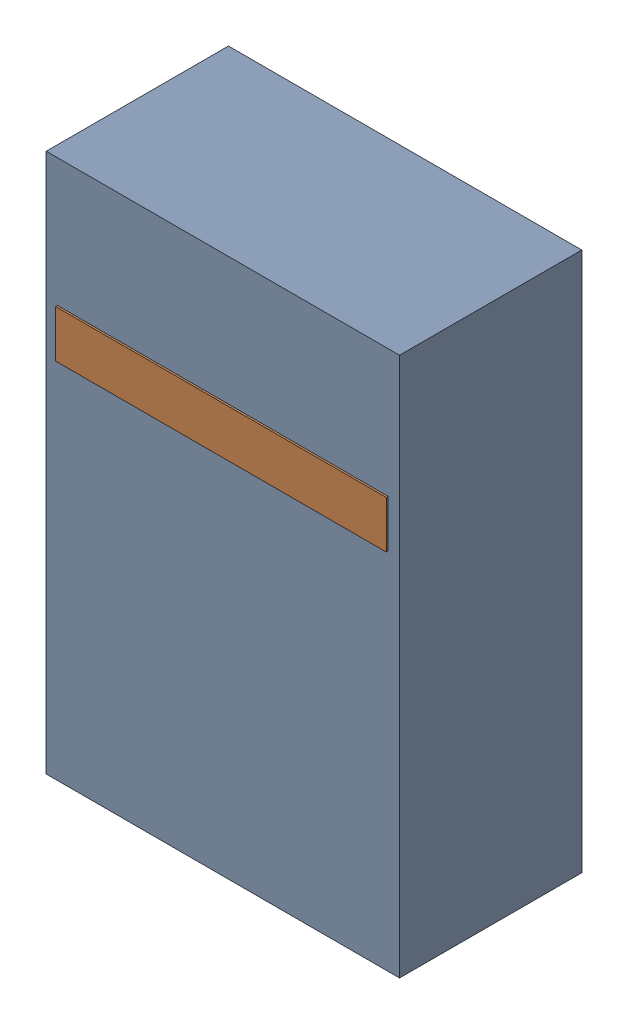
SolidWorks assembly D39, configuration Default. Lengths in mm.
Overall size (1.9 2.9 0.99).
4 component instances, 2 part files, 0 mates.
Components (placement in the parent):
- 1151710376-1: 1151710376 [Default] at (167.767 62.992 0) size (1.9 2.9 0.98)
  - Extruded-1: Extruded [Default] at origin size (1.9 2.9 0.98)
- 1151710512-1: 1151710512 [Default] at (167.767 63.627 0.95) size (1.78 0.25 0.04)
  - Extruded_1-1: Extruded_1 [Default] at origin size (1.78 0.25 0.04)
